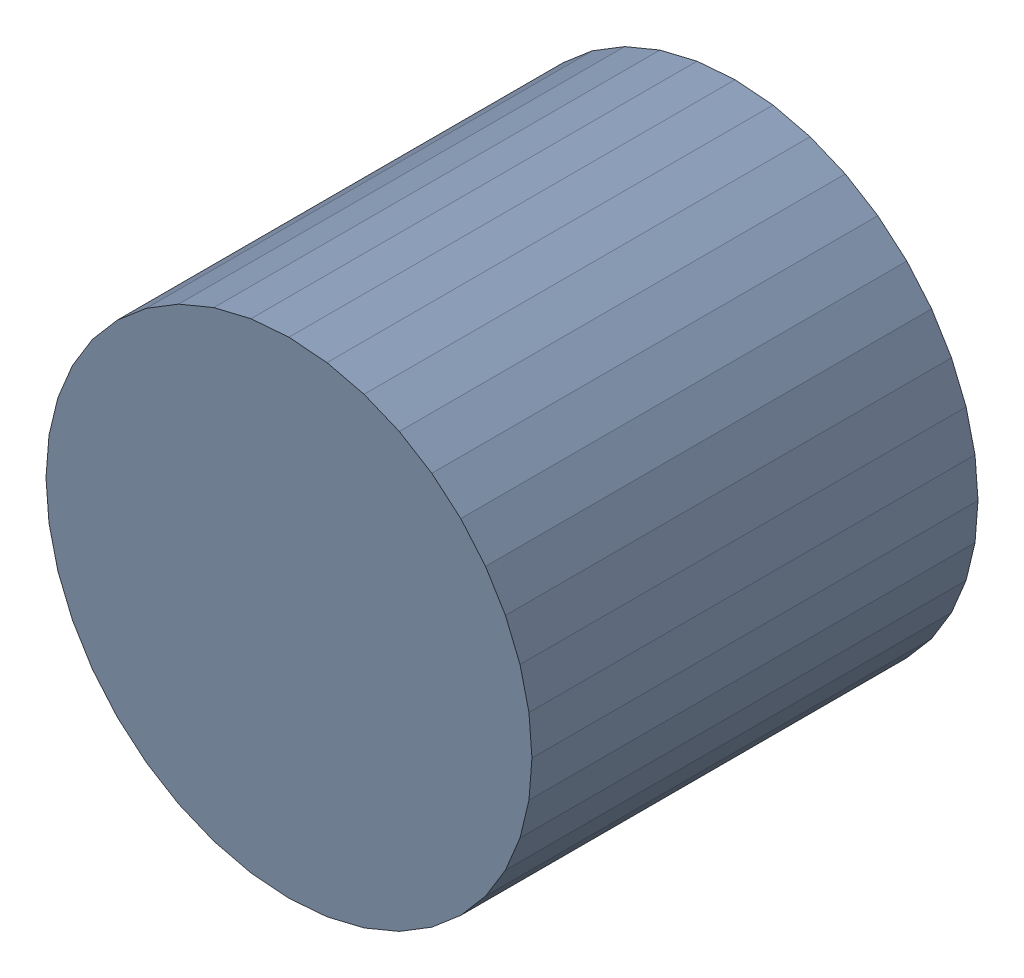
SolidWorks assembly C10Kanaloa_v2.0.0_Motor, configuration Default. Lengths in mm.
Overall size (6.32 6.32 5.8).
2 component instances, 1 part files, 0 mates.
Components (placement in the parent):
- 352892112-1: 352892112 [Default] at (88.9 44.45 0) size (6.32 6.32 5.8)
  - Extruded_11-1: Extruded_11 [Default] at origin size (6.32 6.32 5.8)
